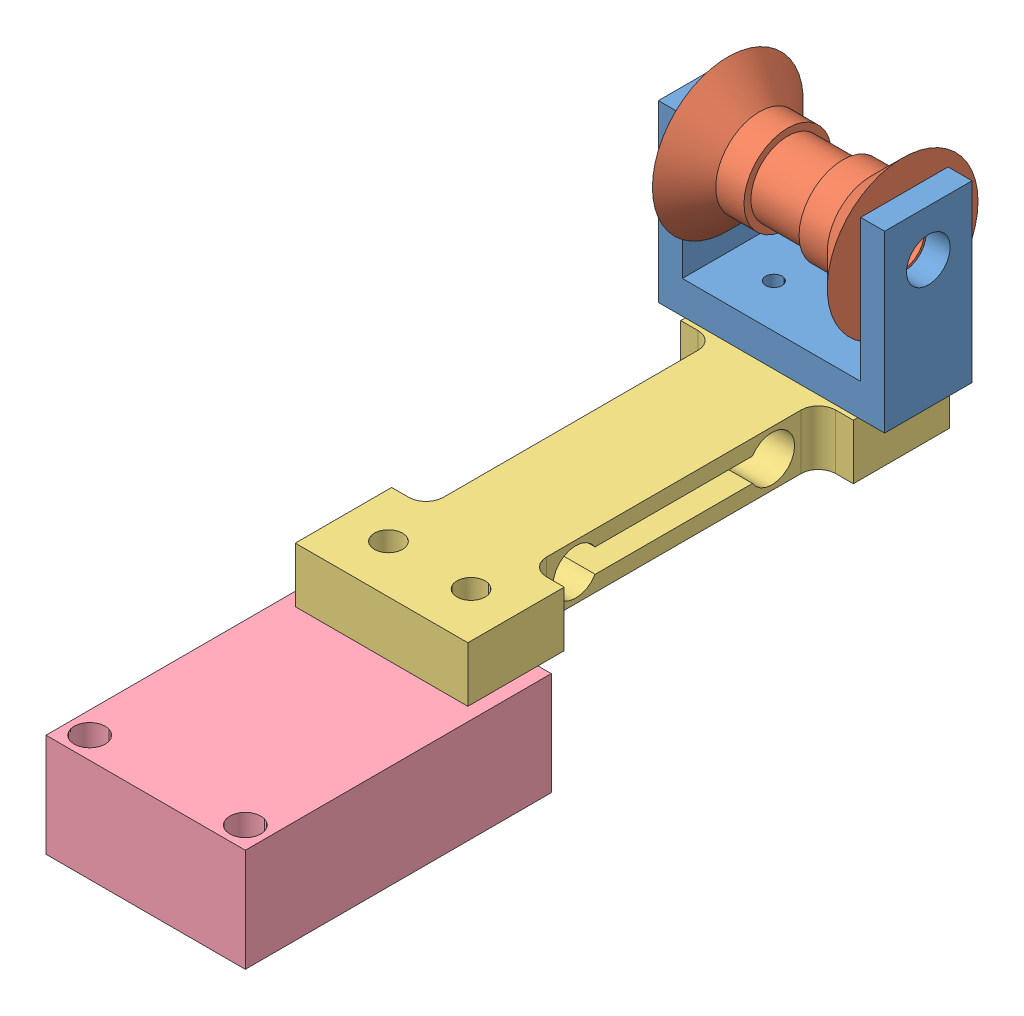
SolidWorks assembly tension_sensor_v2, configuration Default. Lengths in mm.
Overall size (16.44 26.29 54.11).
4 component instances, 4 part files, 8 mates.
Components (placement in the parent):
- tension_roller_mount_v2-1: tension_roller_mount_v2 [Default] at (-23.9397 -15.8976 -24.823) size (16.44 12.7 6.35)
- tension_roller_v2-1: tension_roller_v2 [Default] at (-23.9397 -6.5758 -24.823) size (12.7 10.95 10.95)
- 100g_load_cell_RB-Phi-203-1: 100g_load_cell_RB-Phi-203 [Default] at (-20.2089 -15.8976 -28.323) x (1 0 0) z (0 -1 0) size (12.54 35 4)
- load_cell_vertical_base_v2-1: load_cell_vertical_base_v2 [Default] at (-23.9397 -27.3906 12.702) x (-1 0 0) z (0 0 -1) size (14.48 7.49 22.23)
Mates (geometry in assembly coordinates):
- Coincident2: coincident anti-aligned: plane of tension_roller_mount_v2-1 through (-15.7221 -15.8976 -27.998) normal (0 -1 0); plane of 100g_load_cell_RB-Phi-203-1 through (-30.2089 -15.8976 6.677) normal (0 1 0)
- Concentric2: concentric anti-aligned: cylinder of tension_roller_mount_v2-1 through (-20.9397 -13.5164 -24.823) axis (0 1 0) radius 0.5956; cylinder of 100g_load_cell_RB-Phi-203-1 through (-20.9397 -19.8976 -24.823) axis (0 -1 0) radius 1.025
- Concentric3: concentric anti-aligned: cylinder of tension_roller_mount_v2-1 through (-26.9397 -13.5164 -24.823) axis (0 1 0) radius 0.5956; cylinder of 100g_load_cell_RB-Phi-203-1 through (-26.9397 -19.8976 -24.823) axis (0 -1 0) radius 1.025
- Concentric5: concentric anti-aligned: cylinder of tension_roller_mount_v2-1 through (-32.1573 -6.5758 -24.823) axis (1 0 0) radius 1.5875; cylinder of tension_roller_v2-1 through (-17.5897 -6.5758 -24.823) axis (-1 0 0) radius 1.5875
- Concentric6: concentric anti-aligned: cylinder of 100g_load_cell_RB-Phi-203-1 through (-20.9397 -19.8976 3.177) axis (0 -1 0) radius 1.025; circle of load_cell_vertical_base_v2-1
- Concentric7: concentric anti-aligned: cylinder of 100g_load_cell_RB-Phi-203-1 through (-26.9397 -19.8976 3.177) axis (0 -1 0) radius 1.025; circle of load_cell_vertical_base_v2-1
- Coincident3: coincident anti-aligned: plane of 100g_load_cell_RB-Phi-203-1 through (-30.2089 -19.8976 6.677) normal (0 -1 0); plane of load_cell_vertical_base_v2-1 through (-31.1787 -19.8976 23.8145) normal (0 1 0)
- Width1: width anti-aligned: plane of tension_roller_mount_v2-1 through (-30.4167 -30.3243 -21.648) normal (1 0 0); plane of tension_roller_mount_v2-1 through (-17.4627 -30.3243 -21.648) normal (-1 0 0); plane of tension_roller_v2-1 through (-30.2897 -6.5758 -24.823) normal (-1 0 0); plane of tension_roller_v2-1 through (-17.5897 -6.5758 -24.823) normal (1 0 0)
